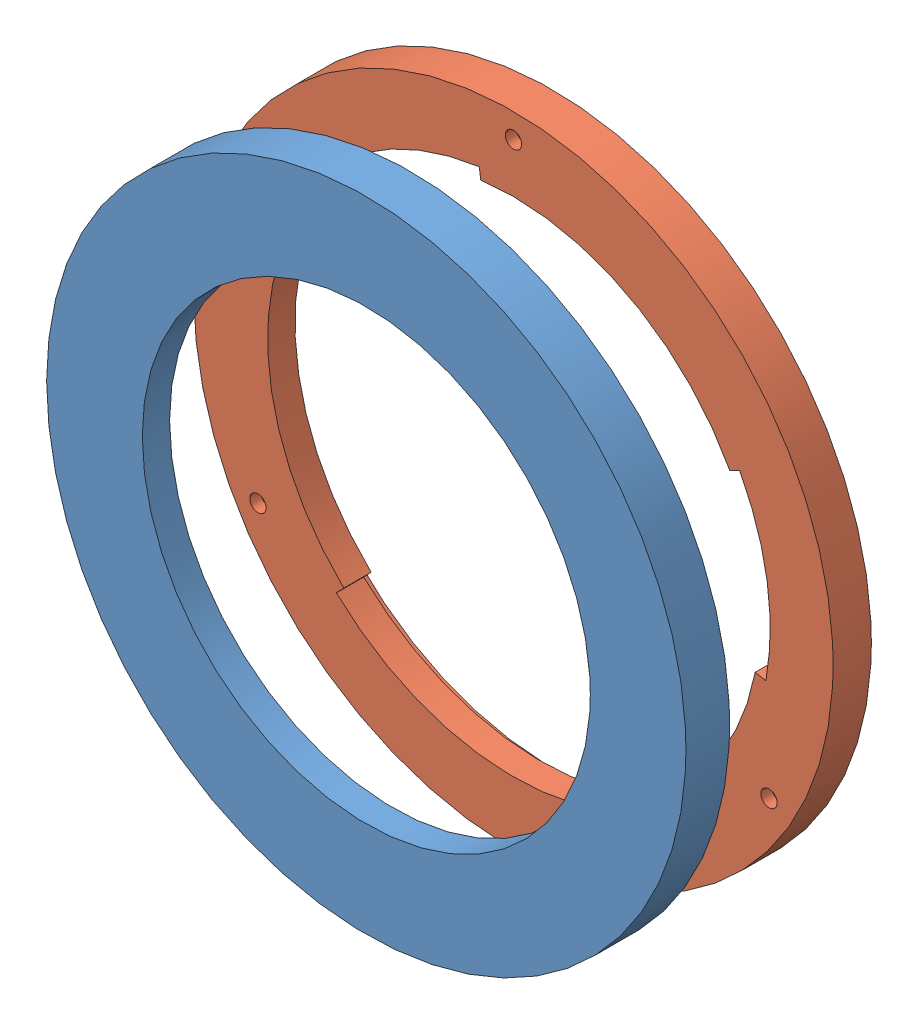
SolidWorks assembly Assem1, configuration Default. Lengths in mm.
Overall size (58.5 58.5 16.97).
2 component instances, 2 part files, 3 mates.
Components (placement in the parent):
- Body1-1: Body1 [Default] at origin size (58.5 58.5 4.75)
- Body2-1: Body2 [Default] at (0 0 -9.4683) size (58.5 58.5 3.5)
Mates (geometry in assembly coordinates):
- Coincident1: coincident aligned: cylinder of Body1-1 through (0 27 2.75) axis (0 0 1) radius 0.75; circle of Body2-1
- Coincident2: coincident: plane of Body1-1 through (0 0 3.5) normal (0 0 -1); plane of Body2-1 through (16.7358 5.8124 3.5) normal (0 0 1)
- Concentric1: concentric aligned: cylinder of Body1-1 through (23.3827 -13.5 2.75) axis (0 0 1) radius 0.75; cylinder of Body2-1 through (23.3827 -13.5 -6.9683) axis (0 0 1) radius 0.75
